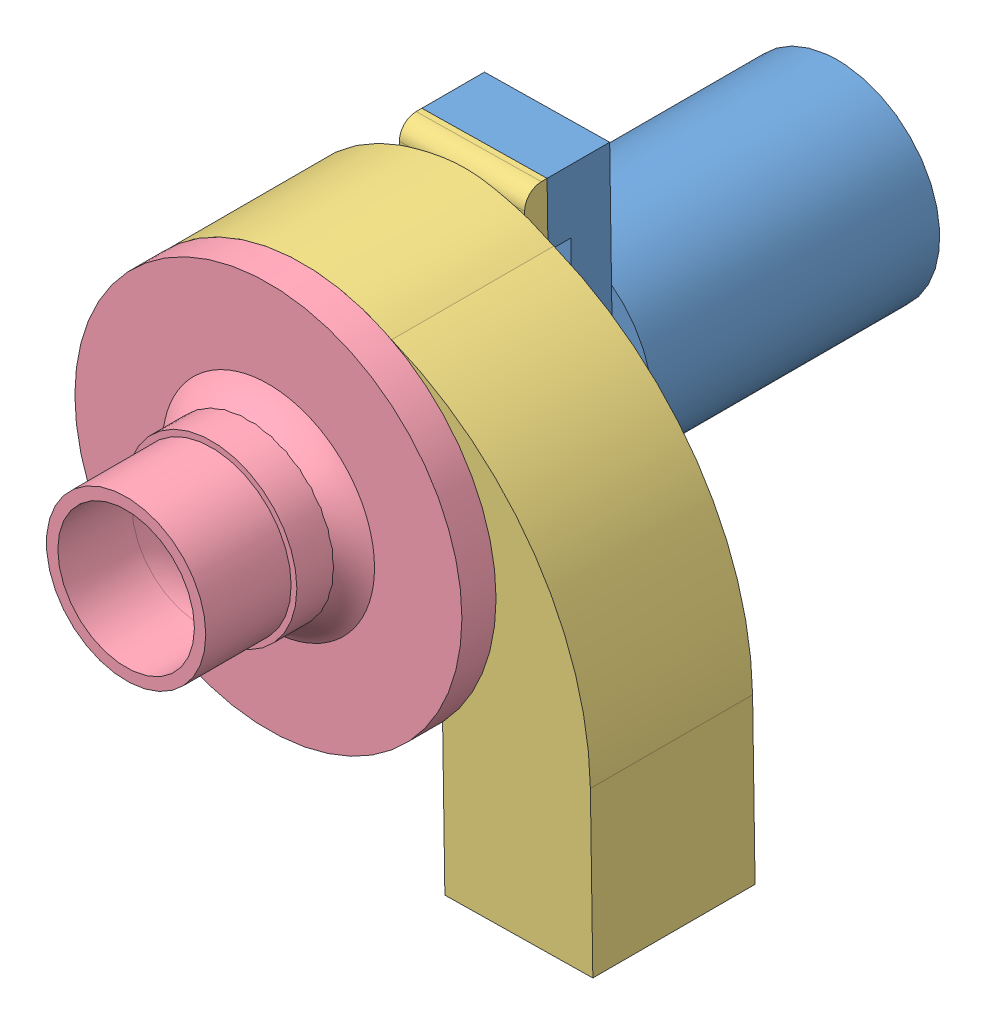
SolidWorks assembly montagem_compressor, configuration Default. Lengths in mm.
Overall size (92.07 91.61 132).
4 component instances, 4 part files, 7 mates.
Components (placement in the parent):
- motor-1: motor [Default] at (39.5699 72.7608 41.1079) x (-0.015103 0.999886 0) z (0 0 1) size (71.5 35.9 94.5)
- Turbocharger Impeller-1: Turbocharger Impeller [Default] at (39.5699 72.7608 110.6079) x (-0.966978 0.254858 0) z (0.254858 0.966978 0) size (67.21 24.5 67.29)
- carcaca_traseira-1: carcaca_traseira [Default] at (39.5699 72.7608 135.1079) x (-0.999886 -0.015103 0) z (0 0 -1) size (84.25 85.75 32.5)
- tampa_compressor-1: tampa_compressor [Default] at (39.5699 72.7608 138.1079) x (1 0 0) z (0 0 -1) size (68 68 48)
Mates (geometry in assembly coordinates):
- Concentric1: concentric anti-aligned: cylinder of motor-1 through (39.5699 72.7608 128.6079) axis (0 0 -1) radius 3; cylinder of Turbocharger Impeller-1 through (39.5699 72.7608 122.8579) axis (0 0 1) radius 3
- Concentric2: concentric aligned: cylinder of motor-1 through (39.5699 72.7608 128.6079) axis (0 0 -1) radius 3; cylinder of carcaca_traseira-1 through (39.5699 72.7608 157.6079) axis (0 0 -1) radius 3.5
- Parallel2: parallel aligned: plane of motor-1 through (29.1111 36.8487 98.6079) normal (-0.999886 -0.015103 0); plane of carcaca_traseira-1 through (63.8171 73.127 232.9908) normal (-0.999886 -0.015103 0)
- Coincident6: coincident anti-aligned: plane of motor-1 through (39.5699 72.7608 102.6079) normal (0 0 1); plane of carcaca_traseira-1 through (39.5699 72.7608 102.6079) normal (0 0 -1)
- Coincident8: coincident anti-aligned: plane of carcaca_traseira-1 through (39.5699 72.7608 135.1079) normal (0 0 1); plane of tampa_compressor-1 through (39.5699 72.7608 135.1079) normal (0 0 -1)
- Distance1: distance = 1 mm anti-aligned: plane of Turbocharger Impeller-1 through (69.0627 64.9876 110.6079) normal (0 0 -1); plane of carcaca_traseira-1 through (39.5699 72.7608 109.6079) normal (0 0 1)
- Concentric3: concentric aligned: cylinder of carcaca_traseira-1 through (39.5699 72.7608 109.6079) axis (0 0 1) radius 31.25; cylinder of tampa_compressor-1 through (39.5699 72.7608 121.1079) axis (0 0 1) radius 31
